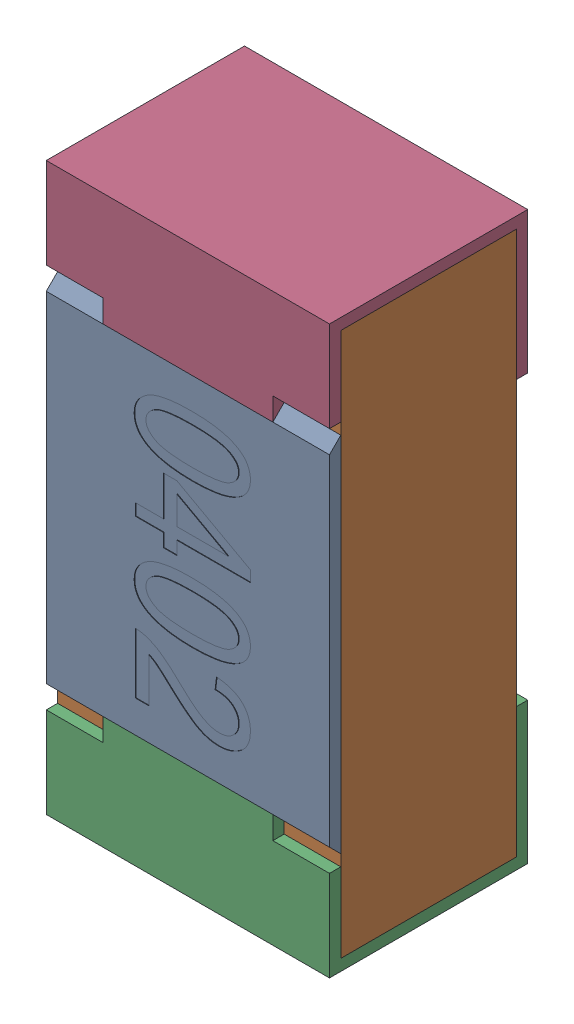
SolidWorks assembly R13, configuration Standard. Lengths in mm.
Overall size (0.5 1 0.35).
5 component instances, 4 part files, 0 mates.
Components (placement in the parent):
- R13-subassembly-1-1: R13-subassembly-1 [Standard] at (-0.2 18.0999 0) x (0 -1 0) z (0 0 1) size (1 0.5 0.35)
  - User Library-R_0402-1: User Library-R_0402 [Standard] at origin size (0.64 0.5 0.02)
  - User Library-R_0402-1-1: User Library-R_0402-1 [Standard] at origin size (0.96 0.5 0.31)
  - User Library-R_0402-2-1: User Library-R_0402-2 [Standard] at origin size (0.25 0.5 0.35)
  - User Library-R_0402-3-1: User Library-R_0402-3 [Standard] at origin size (0.25 0.5 0.35)
